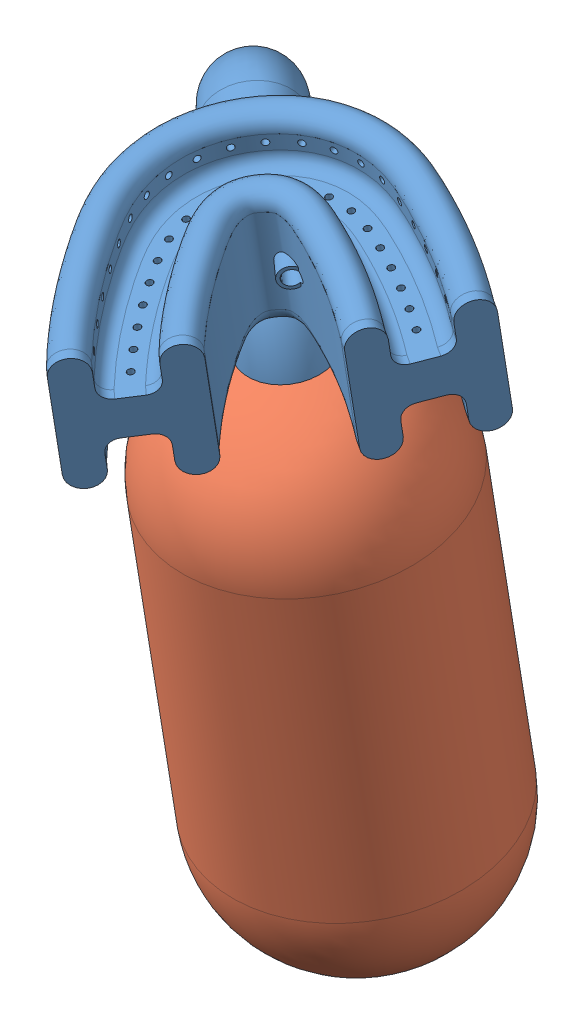
SolidWorks assembly NewBrush, configuration Default. Lengths in mm.
Overall size (158.34 275.84 193.37).
4 component instances, 4 part files, 11 mates.
Components (placement in the parent):
- mouth piece-1: mouth piece [Default] at (23.1267 77.7028 167.9612) x (0.66806 0.118383 -0.73463) z (0.743555 -0.144254 0.65293) size (100.25 90 119.39)
- liquid container-1: liquid container [Default] at (-35.9855 -8.1606 100.369) x (-0.66806 -0.118383 0.73463) z (-0.743555 0.144254 -0.65293) size (80 180 80)
- motor-1: motor [Default] at (-38.1363 -81.8431 86.5394) x (-0.66806 -0.118383 0.73463) z (-0.743555 0.144254 -0.65293) size (50 30 30)
- fluid lines-1: fluid lines [Default] at (-37.8495 -72.0188 88.3833) x (0.66806 0.118383 -0.73463) z (0.743555 -0.144254 0.65293) size (35.1 101.51 5.2)
Mates (geometry in assembly coordinates):
- Parallel1: parallel anti-aligned: plane of mouth piece-1 through (-35.1678 19.8525 105.6268) normal (-0.028677 -0.982434 -0.184395); plane of liquid container-1 through (-35.9855 -8.1606 100.369) normal (0.028677 0.982434 0.184395)
- Parallel2: parallel anti-aligned: plane of mouth piece-1 through (23.1267 77.7028 167.9612) normal (0.743555 -0.144254 0.65293); plane of liquid container-1 through (-35.9855 -8.1606 100.369) normal (-0.743555 0.144254 -0.65293)
- Coincident5: coincident aligned: line of mouth piece-1 through (-33.1604 88.6228 118.5344) axis (0.028677 0.982434 0.184395); axis of liquid container-1 through (-36.6738 -31.739 95.9435) axis (0.028677 0.982434 0.184395)
- Lock1: lock: unknown of mouth piece-1; unknown of liquid container-1
- Coincident6: coincident aligned: plane of liquid container-1 through (-35.9855 -8.1606 100.369) normal (-0.66806 -0.118383 0.73463); plane of motor-1 through (-38.1363 -81.8431 86.5394) normal (-0.66806 -0.118383 0.73463)
- Concentric3: concentric anti-aligned: cylinder of liquid container-1 through (-36.4662 -81.5472 84.7028) axis (-0.66806 -0.118383 0.73463) radius 15; cylinder of motor-1 through (-54.8378 -84.8027 104.9051) axis (0.66806 0.118383 -0.73463) radius 15
- Parallel6: parallel aligned: plane of liquid container-1 through (-35.9855 -8.1606 100.369) normal (0.028677 0.982434 0.184395); plane of motor-1 through (-38.1363 -81.8431 86.5394) normal (0.028677 0.982434 0.184395)
- Parallel7: parallel aligned: plane of motor-1 through (-38.1363 -81.8431 86.5394) normal (0.028677 0.982434 0.184395); plane of fluid lines-1 through (-37.8495 -72.0188 88.3833) normal (0.028677 0.982434 0.184395)
- Concentric4: concentric anti-aligned: cylinder of motor-1 through (-47.7271 -68.8824 100.3247) axis (-0.028677 -0.982434 -0.184395) radius 2.5; cylinder of fluid lines-1 through (-48.0999 -81.654 97.9276) axis (0.028677 0.982434 0.184395) radius 2.5
- Concentric5: concentric anti-aligned: cylinder of motor-1 through (-27.6853 -65.3309 78.2858) axis (-0.028677 -0.982434 -0.184395) radius 2.5; cylinder of fluid lines-1 through (-28.0581 -78.1025 75.8887) axis (0.028677 0.982434 0.184395) radius 2.5
- Coincident8: coincident aligned: circle of liquid container-1; circle of fluid lines-1
